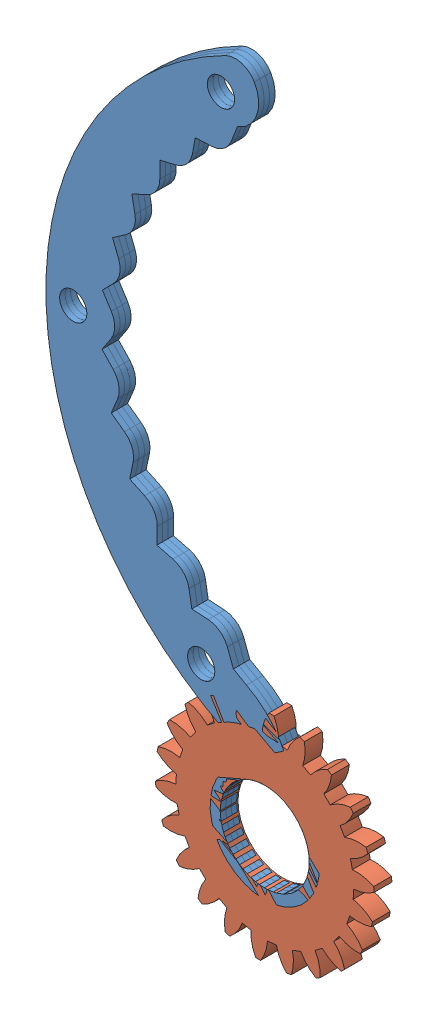
SolidWorks assembly handle 2, configuration Default. Lengths in mm.
Overall size (32.9 73.09 1.63).
4 component instances, 2 part files, 9 mates.
Components (placement in the parent):
- kiskac1-1: kiskac1 [Varsayılan] at (65.4233 86.2581 103.6139) size (25 65.23 0.5)
- gear-3: gear [Default] at (35.7628 47.2729 102.4149) x (0 0 1) z (-0.933673 -0.358127 0) size (1.63 19.86 20.01)
- kiskac1-2: kiskac1 [Varsayılan] at (65.4233 86.2581 103.1139) size (25 65.23 0.5)
- kiskac1-3: kiskac1 [Varsayılan] at (65.4233 86.2581 102.6139) size (25 65.23 0.5)
Mates (geometry in assembly coordinates):
- Concentric2: concentric aligned: circle of gear-3; circle of kiskac1-1
- Coincident1: coincident aligned: plane of kiskac1-1 through (30.8288 101.4741 104.3639) normal (0 0 1); plane of gear-3 through (49.409 39.6267 104.3639) normal (0 0 1)
- Coincident2: coincident anti-aligned: plane of kiskac1-1 through (30.8288 101.4741 103.8639) normal (0 0 -1); plane of kiskac1-2 through (30.8288 101.4741 103.8639) normal (0 0 1)
- Concentric3: concentric aligned: circle of kiskac1-1; circle of kiskac1-2
- Concentric4: concentric aligned: circle of kiskac1-1; circle of kiskac1-2
- Concentric5: concentric aligned: circle of kiskac1-1; circle of kiskac1-2
- Coincident5: coincident anti-aligned: plane of kiskac1-2 through (30.8288 101.4741 103.3639) normal (0 0 -1); plane of kiskac1-3 through (30.8288 101.4741 103.3639) normal (0 0 1)
- Concentric6: concentric aligned: circle of kiskac1-1; circle of kiskac1-3
- Concentric7: concentric aligned: circle of kiskac1-1; circle of kiskac1-3
